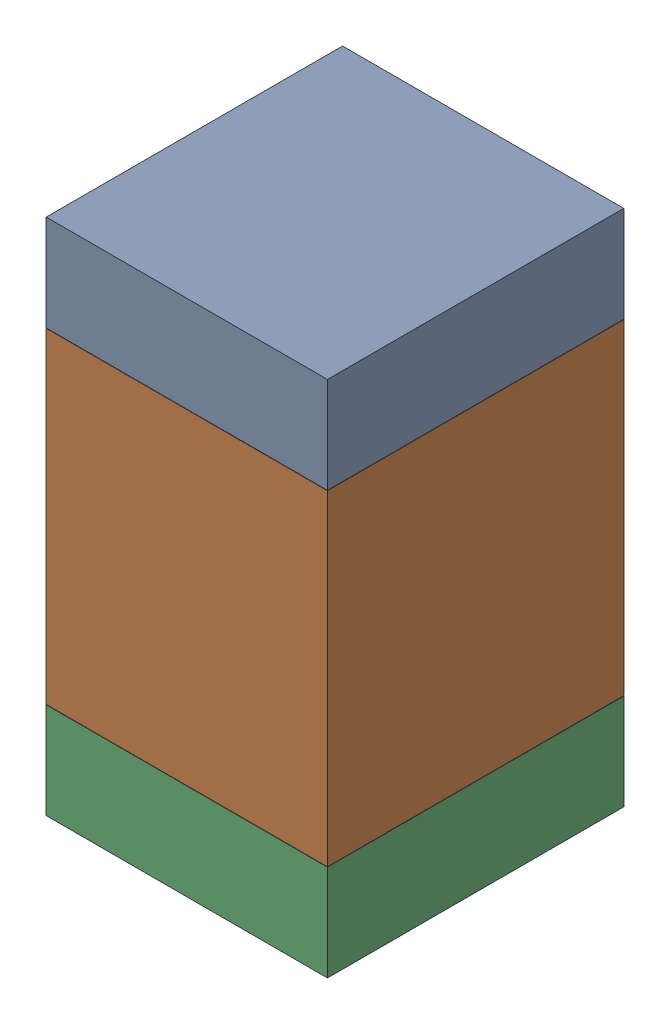
SolidWorks assembly C16, configuration Default. Lengths in mm.
Overall size (0.95 1.75 1).
6 component instances, 2 part files, 0 mates.
Components (placement in the parent):
- 6575495072-1: 6575495072 [Default] at (9.652 19.1275 0) size (0.95 0.32 1)
  - Extruded_6-1: Extruded_6 [Default] at origin size (0.95 0.32 1)
- 6575494912-1: 6575494912 [Default] at (9.652 18.415 0) size (0.95 1.1 1)
  - Extruded_7-1: Extruded_7 [Default] at origin size (0.95 1.1 1)
- 6575495072-2: 6575495072 [Default] at (9.652 17.7025 0) size (0.95 0.32 1)
  - Extruded_6-1: Extruded_6 [Default] at origin size (0.95 0.32 1)
